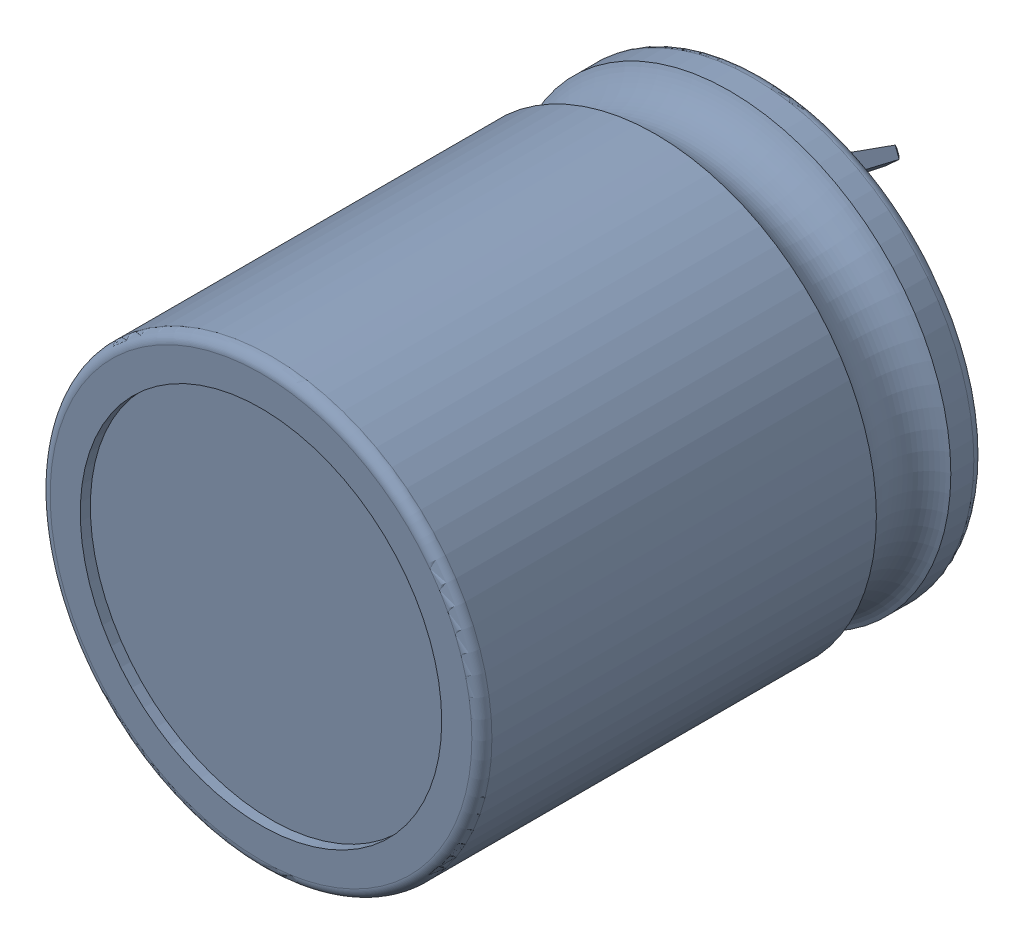
SolidWorks assembly C5, configuration Default. Lengths in mm.
Overall size (22 22 31.01).
4 component instances, 2 part files, 0 mates.
Components (placement in the parent):
- Capacitor22x25-1: Capacitor22x25 [Default] at (143.3021 20.3362 -3.686) x (0 -1 0) z (-1 0 0) size (22 31.01 22)
  - User_Library-ECEC2DP271BJ-1: User_Library-ECEC2DP271BJ [Default] at (8.9531 3.6858 17.317) size (22 25.01 22)
  - User_Library-CAP_EL_SNAP-IN_10_35x45_Valor_predeterminado-1: User_Library-CAP_EL_SNAP-IN_10_35x45_Valor_predeterminado [Default] at (14.4607 11.8368 29.4898) x (0.642788 0 0.766044) z (-0.766044 0 0.642788) size (3.5 7.01 5.68)
  - User_Library-CAP_EL_SNAP-IN_10_35x45_Valor_predeterminado-2: User_Library-CAP_EL_SNAP-IN_10_35x45_Valor_predeterminado [Default] at (2.8917 11.8368 4.8301) x (-0.67559 0 -0.737277) z (0.737277 0 -0.67559) size (3.5 7.01 5.68)
